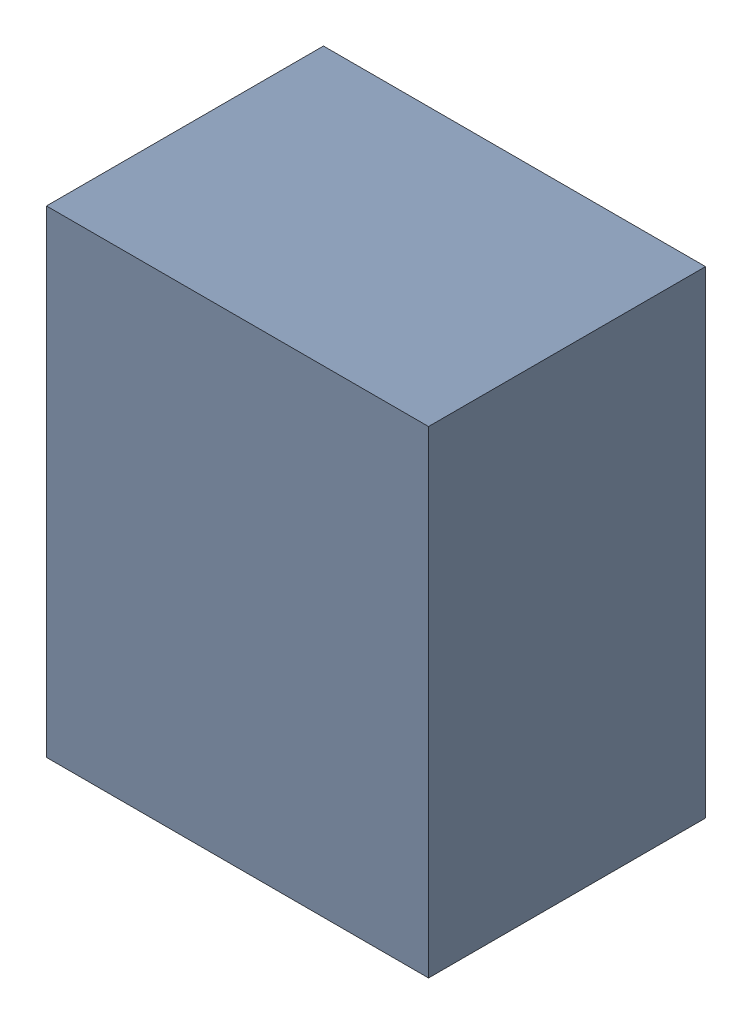
SolidWorks assembly U21, configuration Default. Lengths in mm.
Overall size (0.8 1 0.58).
2 component instances, 1 part files, 0 mates.
Components (placement in the parent):
- 836751984-1: 836751984 [Default] at (133.05 58.5 0.5) size (0.8 1 0.58)
  - Extruded_32-1: Extruded_32 [Default] at origin size (0.8 1 0.58)
